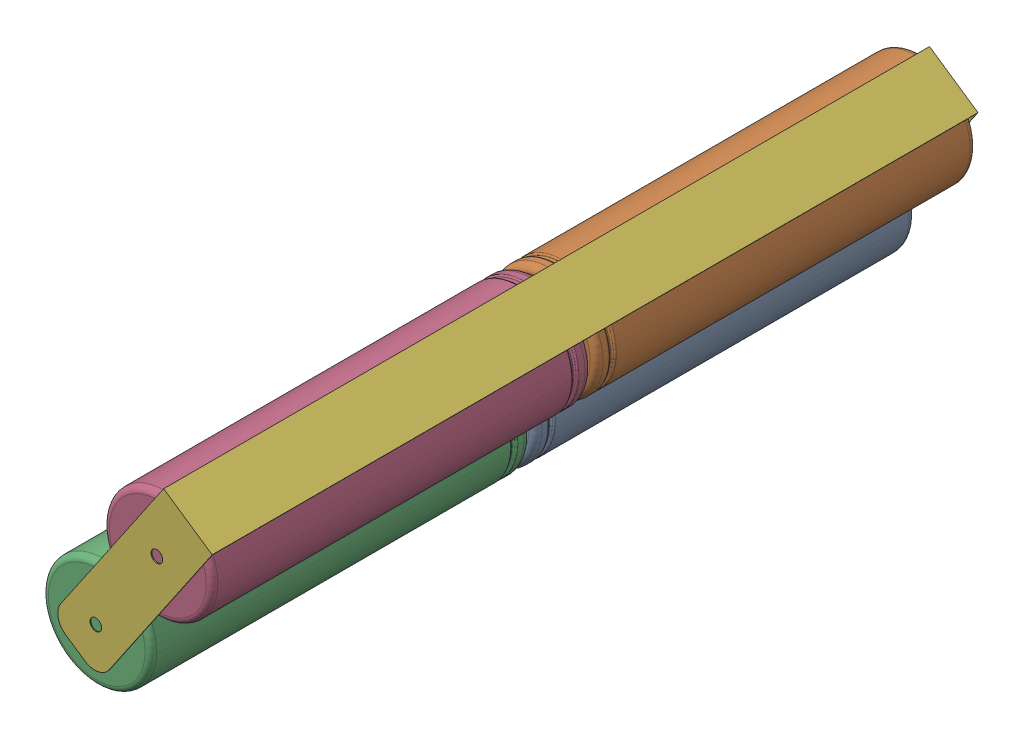
SolidWorks assembly 1s4p_battery_pack, configuration Default. Lengths in mm.
Overall size (34.94 39.81 130.65).
6 component instances, 3 part files, 15 mates.
Components (placement in the parent):
- 18650_battery-1: 18650_battery [Default] at (28.7291 45.9474 42.0397) size (18.5 18.5 65)
- 18650_battery-2: 18650_battery [Default] at (39.1476 61.2348 42.0397) x (-0.525978 -0.850498 0) z (0 0 1) size (18.5 18.5 65)
- 18650_battery-3: 18650_battery [Default] at (28.7291 45.9474 172.3897) x (-0.330758 0.943716 0) z (0 0 -1) size (18.5 18.5 65)
- 18650_battery-4: 18650_battery [Default] at (39.1476 61.2348 172.3897) x (0.002406 0.999997 0) z (0 0 -1) size (18.5 18.5 65)
- 1s4p_battery_inner_tab-1: 1s4p_battery_inner_tab [Default] at (46.5175 63.1705 107.1897) x (-0.826346 0.563162 0) z (0 0 1) size (10 30.18 0.35)
- 1s4p_battery_outer_tab-1: 1s4p_battery_outer_tab [Default] at (21.0776 43.5985 172.5397) x (0 0 1) z (0.563162 0.826346 0) size (130.65 10 34.15)
Mates (geometry in assembly coordinates):
- Tangent2: tangent anti-aligned: cylinder of 18650-1 through (28.7291 45.9474 42.0397) axis (0 0 -1) radius 9.25; cylinder of 18650-2 through (39.1476 61.2348 42.0397) axis (0 0 -1) radius 9.25
- Parallel2: parallel aligned: cylinder of 18650-3 through (28.7291 45.9474 172.3897) axis (0 0 1) radius 9.25; cylinder of 18650-4 through (39.1476 61.2348 172.3897) axis (0 0 1) radius 9.25
- Tangent4: tangent anti-aligned: cylinder of 18650-3 through (28.7291 45.9474 172.3897) axis (0 0 1) radius 9.25; cylinder of 18650-4 through (39.1476 61.2348 172.3897) axis (0 0 1) radius 9.25
- Coincident1: coincident anti-aligned: plane of 18650-2 through (42.9749 58.8679 107.0397) normal (0 0 1); plane of Battery Inner Tab-1 through (21.3592 44.0117 107.0397) normal (0 0 -1)
- Coincident2: coincident anti-aligned: plane of 18650-1 through (28.7291 50.4474 107.0397) normal (0 0 1); plane of Battery Inner Tab-1 through (21.3592 44.0117 107.0397) normal (0 0 -1)
- Coincident3: coincident anti-aligned: plane of 18650-3 through (32.9758 47.4358 107.3897) normal (0 0 -1); plane of Battery Inner Tab-1 through (21.3592 44.0117 107.3897) normal (0 0 1)
- Coincident4: coincident anti-aligned: plane of 18650-4 through (43.6476 61.224 107.3897) normal (0 0 -1); plane of Battery Inner Tab-1 through (21.3592 44.0117 107.3897) normal (0 0 1)
- Concentric1: concentric aligned: cylinder of 18650-3 through (28.7291 45.9474 172.3897) axis (0 0 1) radius 9.25; cylinder of Battery Inner Tab-1 through (28.7291 45.9474 107.0397) axis (0 0 1) radius 1
- Concentric2: concentric aligned: cylinder of 18650-4 through (39.1476 61.2348 172.3897) axis (0 0 1) radius 9.25; cylinder of Battery Inner Tab-1 through (39.1476 61.2348 107.0397) axis (0 0 1) radius 1
- Concentric3: concentric anti-aligned: cylinder of 18650-1 through (28.7291 45.9474 42.0397) axis (0 0 -1) radius 9.25; cylinder of Battery Inner Tab-1 through (28.7291 45.9474 107.0397) axis (0 0 1) radius 1
- Concentric4: concentric anti-aligned: cylinder of 18650-2 through (39.1476 61.2348 42.0397) axis (0 0 -1) radius 9.25; cylinder of Battery Inner Tab-1 through (39.1476 61.2348 107.0397) axis (0 0 1) radius 1
- Concentric5: concentric aligned: cylinder of 18650-3 through (28.7291 45.9474 172.3897) axis (0 0 1) radius 9.25; cylinder of Battery Outer Tab-1 through (28.7291 45.9474 39.0613) axis (0 0 1) radius 1
- Concentric6: concentric anti-aligned: cylinder of 18650-1 through (28.7291 45.9474 42.0397) axis (0 0 -1) radius 9.25; cylinder of Battery Outer Tab-1 through (28.7291 45.9474 39.0613) axis (0 0 1) radius 1
- Coincident7: coincident anti-aligned: plane of 18650-1 through (28.7291 54.1974 42.0397) normal (0 0 -1); plane of Battery Outer Tab-1 through (29.3411 37.9669 42.0397) normal (0 0 1)
- Concentric7: concentric aligned: cylinder of 18650-4 through (39.1476 61.2348 172.3897) axis (0 0 1) radius 9.25; cylinder of Battery Outer Tab-1 through (39.1476 61.2348 39.0613) axis (0 0 1) radius 1
